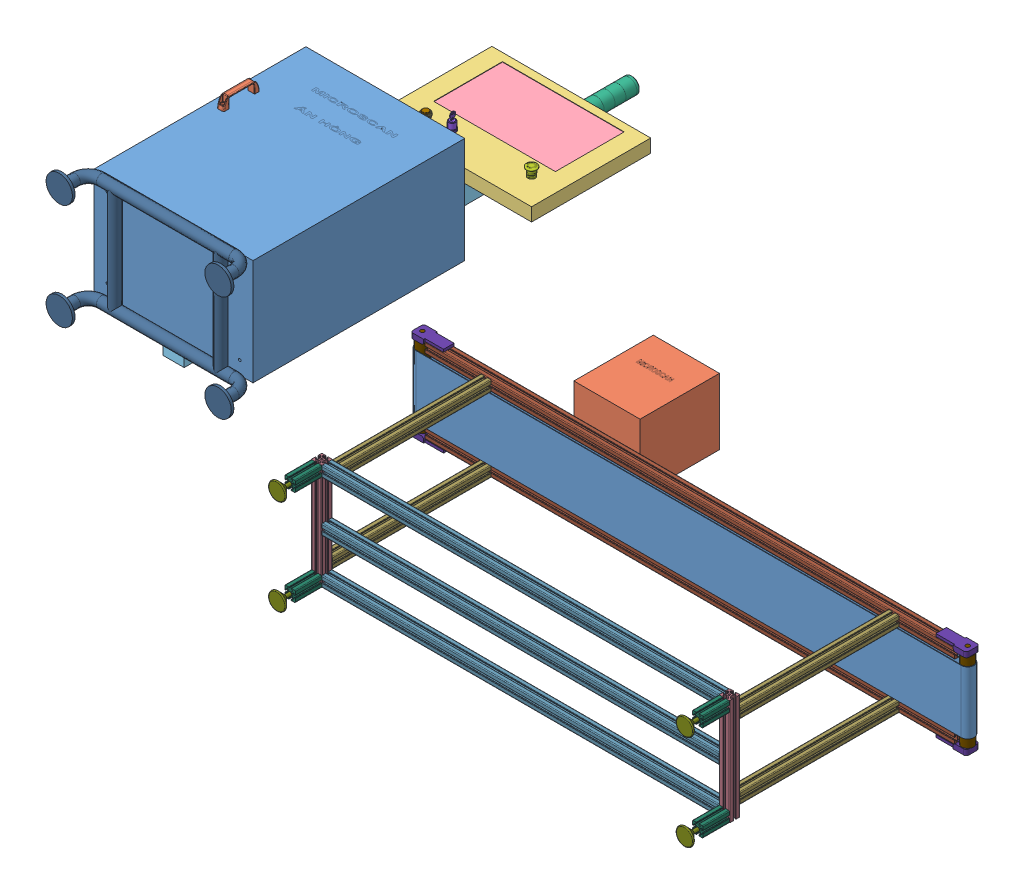
SolidWorks assembly full CPC project 2, configuration Default. Lengths in mm.
Overall size (2701.86 1036.59 1862.4).
58 component instances, 38 part files, 6 mates.
Components (placement in the parent):
- tu dien-1: tu dien [Default] at (34.2688 154.369 734.454) size (700 530 1862.4)
  - tu dien-1: tu dien [Default] at (221.8904 379.7546 416.37) size (600 400 800)
  - 8020-2061-$PARTNUMBER-1: 8020-2061-$PARTNUMBER [Default] at (-32.7798 579.7546 716.6699) x (0 0 1) z (-1 0 0) size (139.17 41.43 26.33)
  - bat man hinh-1: bat man hinh [Default] at (221.8904 179.7546 -61.13) x (1 0 0) z (0 1 0) size (600 450 50)
  - man hinh-1: man hinh [Default] at (221.8904 208.2546 -126.13) x (1 0 0) z (0 1 0) size (500 300 20)
  - thanh bat man hinh-1: thanh bat man hinh [Default] at (221.8904 139.7546 -283.63) size (80 80 1500)
  - User Library-p000557 light tower-1: User Library-p000557 light tower [Default] at (221.8904 139.7546 -283.63) x (0.032421 0.999474 0) z (-0.999474 0.032421 0) size (60 245.1 60)
  - User Library-E Stop Button-1: User Library-E Stop Button [Default] at (421.8904 241.2546 63.87) size (39 70.54 39)
  - G_IC03_XX_28762V-1: G_IC03_XX_28762V [Default] at (121.8933 229.7546 64.07) x (-0.999896 0 0.014408) z (0.014408 0 0.999896) size (29.48 86.4 29.48)
  - dr30e3l-l3gzc-1: dr30e3l-l3gzc [Default] at (23.1032 185.1546 64.858) x (0.429366 0 0.903131) z (0 1 0) size (41 40.2 73.47)
    - dr30e3l-l3gzc_01-1: dr30e3l-l3gzc_01 [Default] at origin size (6.6 6.56 0.7)
    - dr30e3l-l3gzc_02-1: dr30e3l-l3gzc_02 [Default] at origin size (7.7 7.7 1.5)
    - dr30e3l-l3gzc_03-1: dr30e3l-l3gzc_03 [Default] at origin size (39 39 1.5)
    - dr30e3l-l3gzc_04-1: dr30e3l-l3gzc_04 [Default] at origin size (9.1 7.7 3)
    - dr30e3l-l3gzc_05-1: dr30e3l-l3gzc_05 [Default] at origin size (39 39 1.5)
    - dr30e3l-l3gzc_06-1: dr30e3l-l3gzc_06 [Default] at origin size (7.7 7.7 1.5)
    - dr30e3l-l3gzc_07-1: dr30e3l-l3gzc_07 [Default] at origin size (9.1 7.7 3)
    - dr30e3l-l3gzc_08-1: dr30e3l-l3gzc_08 [Default] at origin size (6.6 6.56 0.7)
    - dr30e3l-l3gzc_09-1: dr30e3l-l3gzc_09 [Default] at origin size (7.54 7.17 9.3)
    - dr30e3l-l3gzc_10-1: dr30e3l-l3gzc_10 [Default] at origin size (18.4 29 8.21)
    - dr30e3l-l3gzc_11-1: dr30e3l-l3gzc_11 [Default] at origin size (10 10.77 19.53)
    - dr30e3l-l3gzc_12-1: dr30e3l-l3gzc_12 [Default] at origin size (41 40.2 27.4)
    - dr30e3l-l3gzc_13-1: dr30e3l-l3gzc_13 [Default] at origin size (35 35 10)
    - dr30e3l-l3gzc_14-1: dr30e3l-l3gzc_14 [Default] at origin size (39 39 1.5)
    - dr30e3l-l3gzc_15-1: dr30e3l-l3gzc_15 [Default] at origin size (6.5 6.5 9.3)
    - dr30e3l-l3gzc_16-1: dr30e3l-l3gzc_16 [Default] at origin size (19.8 29.9 44.3)
    - dr30e3l-l3gzc_17-1: dr30e3l-l3gzc_17 [Default] at origin size (26.07 30 22.8)
    - dr30e3l-l3gzc_18-1: dr30e3l-l3gzc_18 [Default] at origin size (39 39 1.5)
    - dr30e3l-l3gzc_19-1: dr30e3l-l3gzc_19 [Default] at origin size (29.15 29.06 9.16)
  - chan de tu-1: chan de tu [Default] at (-80.13 179.7546 1336.37) x (1 0 0) z (0 1 0) size (700 130 500)
- bang_tai-1: bang_tai [Default] at (3876.7553 -966.0283 2574.0152) x (0 1 0) z (-1 0 0) size (453.17 839.84 2119.68)
  - nhom 40x40x2000-1: nhom 40x40x2000 [Default] at (800.1519 1303.1912 1330.5961) size (40 40 2000)
  - nhom 40x40x600-1: nhom 40x40x600 [Default] at (800.1519 1283.1912 3100.5961) x (-1 0 0) z (0 -1 0) size (40 40 600)
  - nhom 40x40x600-2: nhom 40x40x600 [Default] at (800.1519 1283.1912 1560.5961) x (0 0 1) z (0 -1 0) size (40 40 600)
  - nhom 40x40x2000-2: nhom 40x40x2000 [Default] at (1080.1519 1303.1912 1330.5961) size (40 40 2000)
  - nhom 40x40x600-3: nhom 40x40x600 [Default] at (1080.1519 1283.1912 3100.5961) x (-1 0 0) z (0 -1 0) size (40 40 600)
  - nhom 40x40x600-4: nhom 40x40x600 [Default] at (1080.1519 1283.1912 1560.5961) x (0 0 1) z (0 -1 0) size (40 40 600)
  - nhom 40x40x400-1: nhom 40x40x400 [Default] at (740.1519 663.1912 1560.5961) x (0 0 -1) z (1 0 0) size (40 40 400)
  - nhom 40x40x400-2: nhom 40x40x400 [Default] at (740.1519 663.1912 3100.5961) x (0 0 -1) z (1 0 0) size (40 40 400)
  - nhom 40x40x1500-1: nhom 40x40x1500 [Default] at (930.1519 663.1912 1580.5961) size (40 40 1500)
  - nhom 40x40x100-1: nhom 40x40x100 [Default] at (1120.1519 643.1912 1560.5961) x (1 0 0) z (0 -1 0) size (40 40 100)
  - nhom 40x40x100-2: nhom 40x40x100 [Default] at (760.1519 643.1912 1560.5961) x (1 0 0) z (0 -1 0) size (40 40 100)
  - nhom 40x40x100-3: nhom 40x40x100 [Default] at (760.1519 643.1912 3100.5961) x (1 0 0) z (0 -1 0) size (40 40 100)
  - nhom 40x40x100-4: nhom 40x40x100 [Default] at (1120.1519 643.1912 3100.5961) x (1 0 0) z (0 -1 0) size (40 40 100)
  - bat_de-1: bat_de [Default] at (1120.1519 493.1912 3100.5961) x (0.747731 0 -0.664002) z (0.664002 0 0.747731) size (66 80 66)
  - bat_de-2: bat_de [Default] at (1120.1519 493.1912 1560.5961) x (0.747731 0 -0.664002) z (0.664002 0 0.747731) size (66 80 66)
  - bat_de-3: bat_de [Default] at (760.1519 493.1912 3100.5961) x (0.747731 0 -0.664002) z (0.664002 0 0.747731) size (66 80 66)
  - bat_de-4: bat_de [Default] at (760.1519 493.1912 1560.5961) x (0.747731 0 -0.664002) z (0.664002 0 0.747731) size (66 80 66)
  - bat truc-1: bat truc [Default] at (1110.1519 1303.1912 1330.5961) x (0 0 -1) z (-1 0 0) size (120 50 20)
  - bat truc-2: bat truc [Default] at (770.1519 1303.1912 1330.5961) x (0 0 -1) z (1 0 0) size (120 50 20)
  - bat truc-3: bat truc [Default] at (770.1519 1303.1912 3330.5961) x (0 0 1) z (1 0 0) size (120 50 20)
  - bat truc-4: bat truc [Default] at (1110.1519 1303.1912 3330.5961) x (0 0 1) z (-1 0 0) size (120 50 20)
  - truc lan-1: truc lan [Default] at (790.1519 1303.1912 3360.5961) x (0 -0.417649 -0.908609) z (1 0 0) size (45 45 340)
  - truc lan-2: truc lan [Default] at (790.1519 1303.1912 1300.5961) x (0 -0.417649 -0.908609) z (1 0 0) size (45 45 340)
  - Belt2-4^bang_tai-1: Belt2-4^bang_tai [Default] at (940.1519 1303.1912 3360.5961) x (0 0 1) z (-1 0 0) size (2109 49 236) (virtual)
  - nhom 40x40x1500-2: nhom 40x40x1500 [Default] at (1120.1519 663.1912 1580.5961) size (40 40 1500)
  - nhom 40x40x1500-3: nhom 40x40x1500 [Default] at (760.1519 663.1912 1580.5961) size (40 40 1500)
- cover camera-1: cover camera [Default] at (1038.9722 -32.8764 796.324) size (250 250 300)
Mates (geometry in assembly coordinates):
- Coincident1: coincident aligned: plane of tu dien-1/bat_de-2 through (-13.8161 361.7409 1800.824) normal (0 0 1); plane of bang_tai-1/bat_de-3 through (796.0793 -183.4445 2080.824) normal (0 0 1)
- Distance1: distance = 200 mm anti-aligned: plane of tu dien-1/tu dien-1 through (556.1592 334.1236 1950.824) normal (0 -1 0); plane of bang_tai-1/nhom 40x40x2000-2 through (546.1592 134.1236 1287.654) normal (0 1 0)
- Coincident4: coincident aligned: plane of tu dien-1/chan de tu-1 through (-45.8612 734.1236 2080.824) normal (0 0 1); plane of bang_tai-1/bat_de-1 through (796.0793 176.5555 2080.824) normal (0 0 1)
- Distance2: distance = 200 mm anti-aligned: plane of tu dien-1/tu dien-1 through (556.1592 334.1236 1950.824) normal (1 0 0); plane of bang_tai-1/nhom 40x40x600-3 through (756.1592 101.1236 1890.824) normal (-1 0 0)
- Distance3: distance = 150 mm anti-aligned: plane of bang_tai-1/Belt2-4^bang_tai-1 through (2576.1592 -143.8764 1246.324) normal (0 0 -1); plane of cover camera-1 through (1038.9722 -32.8764 1096.324) normal (0 0 1)
- Distance4: distance = 42 mm aligned: plane of cover camera-1 through (1163.9722 92.1236 1096.324) normal (0 1 0); plane of bang_tai-1/nhom 40x40x2000-2 through (546.1592 134.1236 1287.654) normal (0 1 0)
